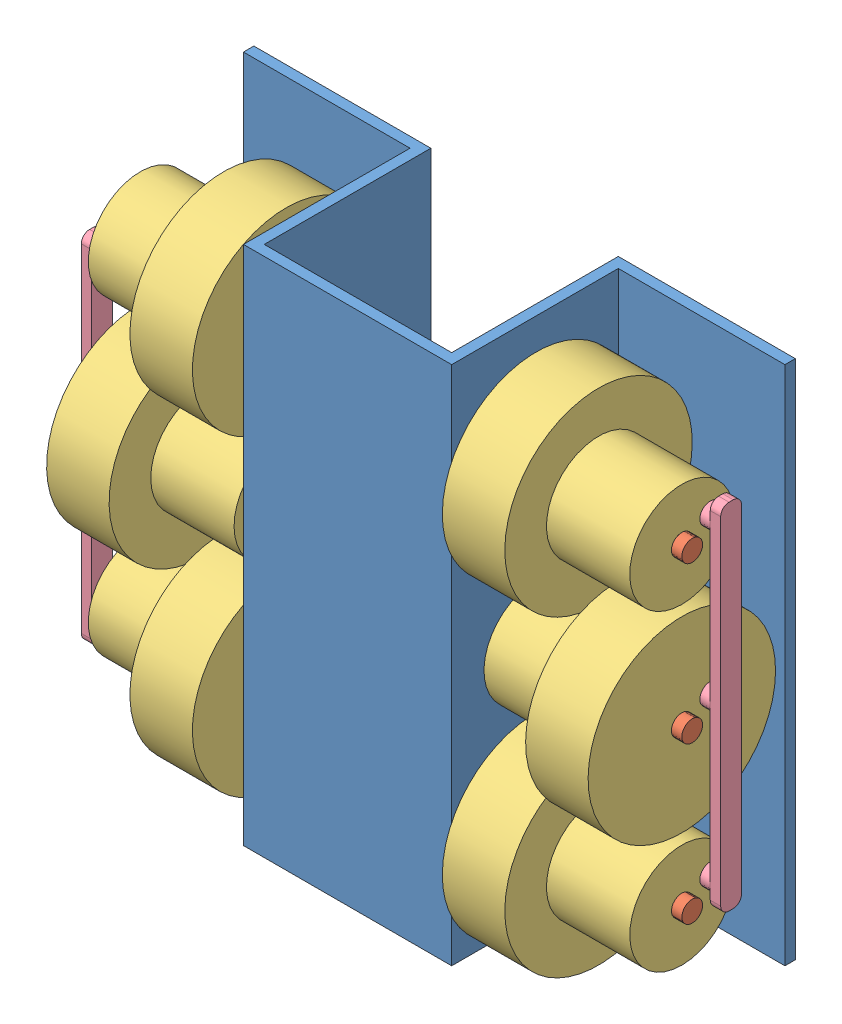
SolidWorks assembly Assemblage1, configuration Défaut. Lengths in mm.
Overall size (280 271.13 121.13).
12 component instances, 4 part files, 26 mates.
Components (placement in the parent):
- CHASSI-1: CHASSI [Défaut] at (36.0102 -93.552 347.5001) size (260 250 85)
- AXE 10X270-1: AXE 10X270 [Défaut] at (-133.9898 106.448 322.0001) x (0 0.248467 0.96864) z (0 0.96864 -0.248467) size (10 260 10)
- AXE 10X270-2: AXE 10X270 [Défaut] at (-133.9898 31.448 322.0001) x (0 -1 0) z (0 0 1) size (10 260 10)
- AXE 10X270-3: AXE 10X270 [Défaut] at (126.0102 -43.552 322.0001) x (0 0.903197 0.429225) z (0 -0.429225 0.903197) size (10 260 10)
- ROUES 90-1: ROUES 90 [Défaut] at (51.0102 106.448 322.0001) x (0 -0.90986 -0.414915) z (1 0 0) size (90 90 70)
- ROUES 90-2: ROUES 90 [Défaut] at (51.0102 -43.552 322.0001) x (0 -0.90986 -0.414915) z (1 0 0) size (90 90 70)
- ROUES 90-3: ROUES 90 [Défaut] at (-138.9898 31.448 322.0001) x (0 0.890039 0.455884) z (1 0 0) size (90 90 70)
- ROUES 90-4: ROUES 90 [Défaut] at (-68.9898 106.448 322.0001) x (0 -0.890039 -0.455884) z (-1 0 0) size (90 90 70)
- ROUES 90-5: ROUES 90 [Défaut] at (-68.9898 -43.552 322.0001) x (0 -0.890039 -0.455884) z (-1 0 0) size (90 90 70)
- ROUES 90-6: ROUES 90 [Défaut] at (121.0102 31.448 322.0001) x (0 0.90986 0.414915) z (-1 0 0) size (90 90 70)
- bielle-1: bielle [Défaut] at (131.0102 122.6718 313.3522) x (0 1 0) z (0 0 1) size (170 20 10)
- bielle-2: bielle [Défaut] at (-148.9898 -60.3902 340.3507) x (0 -1 0) z (0 0 1) size (170 20 10)
Mates (geometry in assembly coordinates):
- Coaxiale1: concentric: cylinder of AXE 10X270-1 through (126.0102 106.448 322.0001) axis (-1 0 0) radius 5; cylinder of CHASSI-1 through (-138.9898 106.448 322.0001) axis (1 0 0) radius 5
- Coaxiale2: concentric: cylinder of AXE 10X270-2 through (126.0102 31.448 322.0001) axis (-1 0 0) radius 5; cylinder of CHASSI-1 through (-138.9898 31.448 322.0001) axis (1 0 0) radius 5
- Coaxiale5: concentric: cylinder of CHASSI-1 through (-138.9898 -43.552 322.0001) axis (1 0 0) radius 5; cylinder of AXE 10X270-3 through (-133.9898 -43.552 322.0001) axis (1 0 0) radius 5
- Distance1: distance = 85 mm: plane of CHASSI-1 through (41.0102 -93.552 347.5001) normal (1 0 0); plane of AXE 10X270-2 through (126.0102 31.448 322.0001) normal (1 0 0)
- Coïncidente8: coincident: plane of AXE 10X270-2 through (126.0102 31.448 322.0001) normal (1 0 0); plane of AXE 10X270-3 through (126.0102 -43.552 322.0001) normal (1 0 0)
- Coïncidente9: coincident: plane of AXE 10X270-1 through (126.0102 106.448 322.0001) normal (1 0 0); plane of AXE 10X270-2 through (126.0102 31.448 322.0001) normal (1 0 0)
- Coaxiale6: concentric: cylinder of AXE 10X270-1 through (126.0102 106.448 322.0001) axis (-1 0 0) radius 5; cylinder of ROUES 90-1 through (51.0102 106.448 322.0001) axis (1 0 0) radius 5
- Coaxiale7: concentric: cylinder of AXE 10X270-2 through (126.0102 31.448 322.0001) axis (-1 0 0) radius 5; cylinder of ROUES 90-6 through (121.0102 31.448 322.0001) axis (-1 0 0) radius 5
- Coaxiale8: concentric: cylinder of AXE 10X270-3 through (-133.9898 -43.552 322.0001) axis (1 0 0) radius 5; cylinder of ROUES 90-2 through (51.0102 -43.552 322.0001) axis (1 0 0) radius 5
- Distance5: distance = 10 mm: plane of ROUES 90-1 through (51.0102 106.448 322.0001) normal (-1 0 0); plane of CHASSI-1 through (41.0102 -93.552 347.5001) normal (1 0 0)
- Coïncidente11: coincident: plane of ROUES 90-1 through (121.0102 106.448 322.0001) normal (1 0 0); plane of ROUES 90-6 through (121.0102 31.448 322.0001) normal (1 0 0)
- Coïncidente12: coincident: plane of ROUES 90-2 through (121.0102 -43.552 322.0001) normal (1 0 0); plane of ROUES 90-6 through (121.0102 31.448 322.0001) normal (1 0 0)
- Coaxiale9: concentric: cylinder of AXE 10X270-2 through (126.0102 31.448 322.0001) axis (-1 0 0) radius 5; cylinder of ROUES 90-3 through (-138.9898 31.448 322.0001) axis (1 0 0) radius 5
- Coaxiale10: concentric: cylinder of AXE 10X270-1 through (126.0102 106.448 322.0001) axis (-1 0 0) radius 5; cylinder of ROUES 90-4 through (-68.9898 106.448 322.0001) axis (-1 0 0) radius 5
- Coaxiale11: concentric: cylinder of AXE 10X270-3 through (-133.9898 -43.552 322.0001) axis (1 0 0) radius 5; cylinder of ROUES 90-5 through (-68.9898 -43.552 322.0001) axis (-1 0 0) radius 5
- Distance6: distance = 10 mm: plane of ROUES 90-5 through (-68.9898 -43.552 322.0001) normal (1 0 0); plane of CHASSI-1 through (-58.9898 -93.552 347.5001) normal (-1 0 0)
- Coïncidente14: coincident: plane of ROUES 90-3 through (-138.9898 31.448 322.0001) normal (-1 0 0); plane of ROUES 90-5 through (-138.9898 -43.552 322.0001) normal (-1 0 0)
- Coïncidente15: coincident: plane of ROUES 90-3 through (-138.9898 31.448 322.0001) normal (-1 0 0); plane of ROUES 90-4 through (-138.9898 106.448 322.0001) normal (-1 0 0)
- Coaxiale12: concentric: cylinder of ROUES 90-2 through (111.0102 -37.3282 308.3522) axis (1 0 0) radius 5; cylinder of bielle-1 through (111.0102 -37.3282 308.3522) axis (1 0 0) radius 5
- Coaxiale13: concentric: cylinder of ROUES 90-6 through (111.0102 37.6718 308.3522) axis (1 0 0) radius 5; cylinder of bielle-1 through (111.0102 37.6718 308.3522) axis (1 0 0) radius 5
- Coaxiale14: concentric: cylinder of ROUES 90-1 through (111.0102 112.6718 308.3522) axis (1 0 0) radius 5; cylinder of bielle-1 through (111.0102 112.6718 308.3522) axis (1 0 0) radius 5
- Coïncidente16: coincident: plane of ROUES 90-6 through (111.0102 37.6718 308.3522) normal (1 0 0); plane of bielle-1 through (111.0102 37.6718 308.3522) normal (-1 0 0)
- Coaxiale15: concentric: cylinder of ROUES 90-4 through (-128.9898 100.8965 335.9349) axis (-1 0 0) radius 5; cylinder of bielle-2 through (-128.9898 100.8965 335.9349) axis (-1 0 0) radius 5
- Coaxiale16: concentric: cylinder of ROUES 90-3 through (-128.9898 25.8965 335.9349) axis (-1 0 0) radius 5; cylinder of bielle-2 through (-128.9898 25.8965 335.9349) axis (-1 0 0) radius 5
- Coaxiale18: concentric: cylinder of ROUES 90-5 through (-128.9898 -49.1035 335.9349) axis (-1 0 0) radius 5; cylinder of bielle-2 through (-128.9898 -49.1035 335.9349) axis (-1 0 0) radius 5
- Coïncidente17: coincident: plane of ROUES 90-3 through (-128.9898 25.8965 335.9349) normal (-1 0 0); plane of bielle-2 through (-128.9898 25.8965 335.9349) normal (1 0 0)
